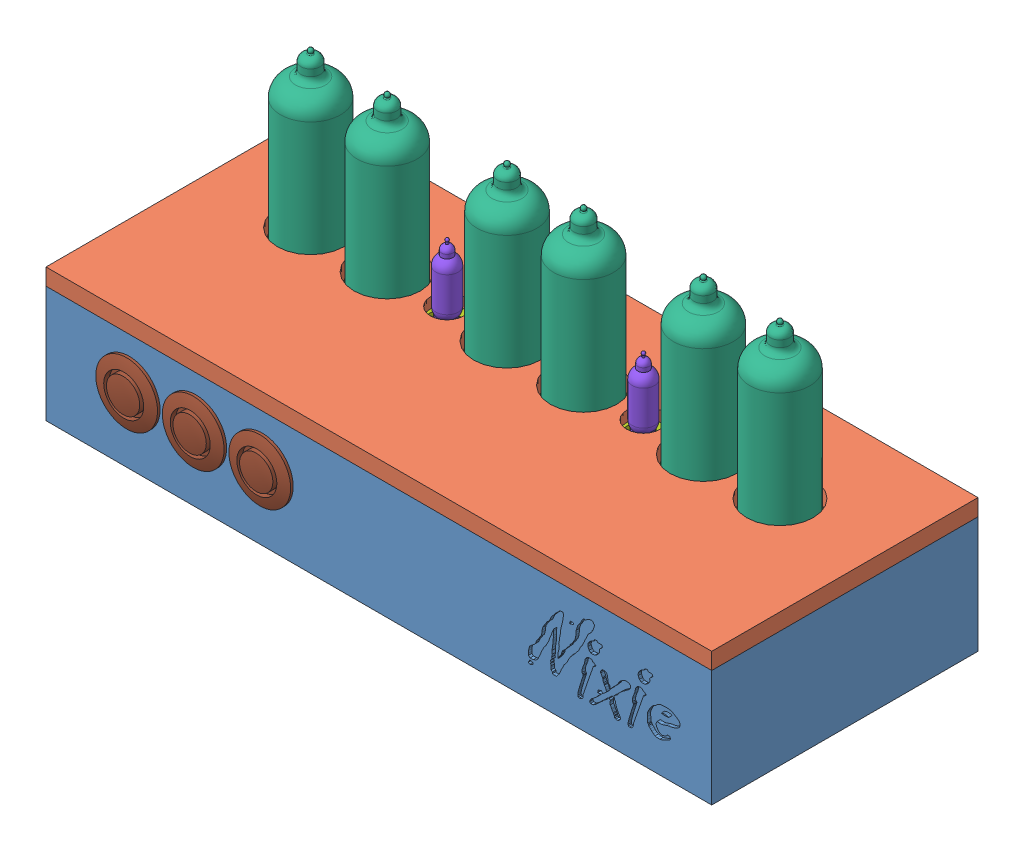
SolidWorks assembly NixieClock, configuration Predeterminado. Lengths in mm.
Overall size (200 86.82 84.28).
32 component instances, 11 part files, 89 mates.
Components (placement in the parent):
- Box-1: Box [Predeterminado] at (5.278 35 -0.0015) x (1 0 0) z (0 -1 0) size (200 80 35)
- Acrylic-1: Acrylic [Predeterminado] at (5.278 40 -0.0015) x (-1 0 0) z (0 -1 0) size (200 80 5)
- Magnet-1: Magnet [Predeterminado] at (101.528 33 36.2485) x (-0.923728 0 -0.383049) z (0 1 0) size (5 5 2)
- Magnet-2: Magnet [Predeterminado] at (101.528 33 -36.2515) x (-0.923728 0 -0.383049) z (0 1 0) size (5 5 2)
- Magnet-3: Magnet [Predeterminado] at (-90.972 33 36.2485) x (-0.923728 0 -0.383049) z (0 1 0) size (5 5 2)
- Magnet-4: Magnet [Predeterminado] at (-90.972 33 -36.2515) x (-0.923728 0 -0.383049) z (0 1 0) size (5 5 2)
- Jack5.5x2.1-1: Jack5.5x2.1 [Predeterminado] at (86.528 23.75 -42.0015) x (0 0 1) z (1 0 0) size (24.25 15.02 15.02)
- Magnet-5: Magnet [Predeterminado] at (101.528 35 36.2485) x (-0.923728 0 -0.383049) z (0 1 0) size (5 5 2)
- Magnet-6: Magnet [Predeterminado] at (101.528 35 -36.2515) x (0.923728 0 0.383049) z (0 1 0) size (5 5 2)
- Magnet-7: Magnet [Predeterminado] at (-90.972 35 36.2485) x (-0.923728 0 -0.383049) z (0 1 0) size (5 5 2)
- Magnet-9: Magnet [Predeterminado] at (-90.972 35 -36.2515) x (-0.923728 0 -0.383049) z (0 1 0) size (5 5 2)
- PCB-SPC-1: PCB-SPC [Predeterminado] at (-79.722 12.9115 19.9985) x (0.499897 0 -0.866085) z (0 1 0) size (6 5.2 16)
- PCB-SPC-2: PCB-SPC [Predeterminado] at (90.278 28.9115 -20.0015) x (1 0 0.000119) z (0 -1 0) size (6 5.2 16)
- PCB-SPC-3: PCB-SPC [Predeterminado] at (90.278 28.9115 19.9985) x (1 0 0.000119) z (0 -1 0) size (6 5.2 16)
- PCB-SPC-4: PCB-SPC [Predeterminado] at (-79.722 12.9115 -20.0015) x (1 0 -0.000119) z (0 1 0) size (6 5.2 16)
- NX-IN14-1: NX-IN14 [Predeterminado] at (75.778 60.573 -10.0016) x (1 0 0) z (0 0 1) size (18 60.3 18)
- Nixie-Board-1-1: Nixie-Board-1 [Predeterminado] at (-84.722 29.323 24.9985) x (1 0 0) z (0 1 0) size (180 50 23.76)
- NX-IN14-2: NX-IN14 [Predeterminado] at (52.778 60.573 -10.0016) x (1 0 0) z (0 0 1) size (18 60.3 18)
- NX-IN14-3: NX-IN14 [Predeterminado] at (16.778 60.573 -10.0016) x (1 0 0) z (0 0 1) size (18 60.3 18)
- NX-IN14-4: NX-IN14 [Predeterminado] at (-6.222 60.573 -10.0016) x (1 0 0) z (0 0 1) size (18 60.3 18)
- NX-IN14-5: NX-IN14 [Predeterminado] at (-42.222 60.573 -10.0016) x (1 0 0) z (0 0 1) size (18 60.3 18)
- NX-IN14-6: NX-IN14 [Predeterminado] at (-65.222 60.573 -10.0016) x (1 0 0) z (0 0 1) size (18 60.3 18)
- NX-IN3-1: NX-IN3 [Predeterminado] at (34.778 45.373 -10.0016) x (-1 0 0) z (0 0 -1) size (7 30.9 6.7)
- NX-IN3-2: NX-IN3 [Predeterminado] at (-24.222 45.373 -10.0016) x (-1 0 0) z (0 0 -1) size (7 30.9 6.7)
- Nixie-Board-2-2: Nixie-Board-2 [Predeterminado] at (-84.722 12.9115 24.9985) x (1 0 0) z (0 1 0) size (180 50 14.63)
- Leg-4: Leg [Predeterminado] at (90.278 7.5 -20.0015) x (1 0 0) z (0 1 0) size (15 25 5)
- Leg-5: Leg [Predeterminado] at (-79.722 7.5 -20.0015) x (1 0 0) z (0 1 0) size (15 25 5)
- Leg-6: Leg [Predeterminado] at (90.278 7.5 19.9985) x (1 0 0) z (0 1 0) size (15 25 5)
- Leg-7: Leg [Predeterminado] at (-79.722 7.5 19.9985) x (1 0 0) z (0 1 0) size (15 25 5)
- Button-4: Button [Predeterminado] at (-69.722 20 26.2785) x (1 0 0) z (0 -1 0) size (21.84 20.06 19.16)
- Button-5: Button [Predeterminado] at (-29.722 20 26.2785) x (1 0 0) z (0 -1 0) size (21.84 20.06 19.16)
- Button-6: Button [Predeterminado] at (-49.722 20 26.2785) x (0 1 0) z (1 0 0) size (21.84 20.06 19.16)
Mates (geometry in assembly coordinates):
- Coincidente1: coincident: plane of assembly; plane of assembly; plane of Box-1 through (5.278 33 -0.0015) normal (0 1 0); plane of Magnet-1 through (101.528 33 36.2485) normal (0 -1 0)
- Concéntrica1: concentric: circle of assembly; circle of assembly; circle of Box-1; circle of Magnet-1
- Coincidente2: coincident: plane of assembly; plane of assembly; plane of Box-1 through (5.278 33 -0.0015) normal (0 1 0); plane of Magnet-2 through (101.528 33 -36.2515) normal (0 -1 0)
- Concéntrica2: concentric: circle of assembly; circle of assembly; circle of Box-1; circle of Magnet-2
- Coincidente3: coincident: plane of assembly; plane of assembly; plane of Box-1 through (5.278 33 -0.0015) normal (0 1 0); plane of Magnet-3 through (-90.972 33 36.2485) normal (0 -1 0)
- Concéntrica3: concentric: circle of assembly; circle of assembly; circle of Box-1; circle of Magnet-3
- Coincidente4: coincident: plane of assembly; plane of assembly; plane of Box-1 through (5.278 33 -0.0015) normal (0 1 0); plane of Magnet-4 through (-90.972 33 -36.2515) normal (0 -1 0)
- Concéntrica4: concentric: circle of assembly; circle of assembly; circle of Box-1; circle of Magnet-4
- Concéntrica5: concentric: circle of assembly; circle of assembly; circle of Box-1; circle of Jack5.5x2.1-1
- Coincidente5: coincident: plane of assembly; plane of assembly; plane of Box-1 through (-94.722 0 -40.0015) normal (0 0 -1); plane of Jack5.5x2.1-1 through (80.278 17.5 -40.0015) normal (0 0 1)
- Paralelo1: parallel: plane of assembly; plane of assembly; plane of Box-1 through (5.278 7.5 -0.0015) normal (0 1 0); plane of Jack5.5x2.1-1 through (85.278 13.9 -17.7515) normal (0 -1 0)
- Coincidente17: coincident: plane of assembly; plane of assembly; plane of Acrylic-1 through (101.528 37 36.2485) normal (0 -1 0); plane of Magnet-5 through (101.528 37 36.2485) normal (0 1 0)
- Coincidente19: coincident: plane of assembly; plane of assembly; plane of Acrylic-1 through (101.528 37 36.2485) normal (0 -1 0); plane of Magnet-5 through (101.528 37 36.2485) normal (0 1 0)
- Coincidente20: coincident: circle of assembly; circle of assembly; circle of Acrylic-1; circle of Magnet-5
- Coincidente21: coincident: plane of assembly; plane of assembly; plane of Acrylic-1 through (101.528 37 -36.2515) normal (0 -1 0); plane of Magnet-6 through (101.528 37 -36.2515) normal (0 1 0)
- Concéntrica10: concentric: circle of assembly; circle of assembly; circle of Acrylic-1; circle of Magnet-6
- Coincidente24: coincident: plane of assembly; plane of assembly; plane of Acrylic-1 through (-90.972 37 36.2485) normal (0 -1 0); plane of Magnet-7 through (-90.972 37 36.2485) normal (0 1 0)
- Concéntrica11: concentric: circle of assembly; circle of assembly; circle of Acrylic-1; circle of Magnet-7
- Coincidente26: coincident: plane of assembly; plane of assembly; plane of Acrylic-1 through (-90.972 37 -36.2515) normal (0 -1 0); plane of Magnet-9 through (-90.972 37 -36.2515) normal (0 1 0)
- Concéntrica12: concentric: circle of assembly; circle of assembly; circle of Acrylic-1; circle of Magnet-9
- Coincidente28: coincident: plane of assembly; plane of assembly; plane of Acrylic-1 through (5.278 35 -0.0015) normal (0 -1 0); plane of Box-1 through (5.278 35 -0.0015) normal (0 1 0)
- Coincidente36: coincident: plane of assembly; plane of assembly; plane of Acrylic-1 through (105.278 35 39.9985) normal (1 0 0); plane of Box-1 through (105.278 0 -40.0015) normal (1 0 0)
- Concéntrica14: concentric: circle of assembly; circle of assembly; circle of NX-IN14-1; circle of Nixie-Board-1-1
- Paralelo4: parallel: line of assembly; line of assembly; line of PCB-SPC-2 through (88.778 28.9115 -22.5996) axis (1 0 0); line of Nixie-Board-1-1 through (95.278 29.323 -25.0015) axis (-1 0 0)
- Coincidente55: coincident: plane of PCB-SPC-2 through (90.278 28.9115 -20.0015) normal (0 1 0); plane of Nixie-Board-1-1 through (-84.722 28.9115 24.9985) normal (0 -1 0)
- Concéntrica27: concentric: unknown of PCB-SPC-2; unknown of Nixie-Board-1-1
- Paralelo5: parallel: line of assembly; line of assembly; line of PCB-SPC-3 through (88.778 28.9115 17.4004) axis (1 0 0); line of Nixie-Board-1-1 through (-84.722 28.9115 24.9985) axis (1 0 0)
- Coincidente58: coincident: plane of PCB-SPC-3 through (90.278 28.9115 19.9985) normal (0 1 0); plane of Nixie-Board-1-1 through (-84.722 28.9115 24.9985) normal (0 -1 0)
- Concéntrica28: concentric: unknown of PCB-SPC-3; unknown of Nixie-Board-1-1
- Paralelo6: parallel: line of assembly; line of assembly; line of PCB-SPC-4 through (-78.222 28.9115 -22.5996) axis (-1 0 0); line of Nixie-Board-1-1 through (95.278 29.323 -25.0015) axis (-1 0 0)
- Coincidente61: coincident: plane of PCB-SPC-4 through (-79.722 28.9115 -20.0015) normal (0 1 0); plane of Nixie-Board-1-1 through (-84.722 28.9115 24.9985) normal (0 -1 0)
- Concéntrica29: concentric: unknown of PCB-SPC-4; unknown of Nixie-Board-1-1
- Paralelo7: parallel: line of assembly; line of assembly; line of PCB-SPC-1 through (-78.222 28.9115 17.4004) axis (-1 0 0); line of Nixie-Board-1-1 through (-84.722 28.9115 24.9985) axis (1 0 0)
- Coincidente64: coincident: plane of PCB-SPC-1 through (-79.722 28.9115 19.9985) normal (0 1 0); plane of Nixie-Board-1-1 through (-84.722 28.9115 24.9985) normal (0 -1 0)
- Concéntrica30: concentric: unknown of PCB-SPC-1; unknown of Nixie-Board-1-1
- Paralelo8: parallel: line of assembly; line of assembly; line of Box-1 through (-94.722 35 -40.0015) axis (1 0 0); line of Nixie-Board-1-1 through (95.278 29.323 -25.0015) axis (-1 0 0)
- Paralelo9: parallel: line of Box-1 through (-94.722 0 -40.0015) axis (0 1 0); line of PCB-SPC-4 through (-81.222 28.9115 -22.5996) axis (0 -1 0)
- Coincidente72: coincident: plane of PCB-SPC-2 through (90.278 12.9115 -20.0015) normal (0 -1 0); plane of Nixie-Board-2-2 through (-84.722 12.9115 24.9985) normal (0 1 0)
- Paralelo11: parallel: line of Nixie-Board-2-2 through (-84.722 12.5 -25.0015) axis (0 0 1); line of Nixie-Board-1-1 through (-84.722 29.323 -25.0015) axis (0 0 1)
- Concéntrica32: concentric: unknown of Nixie-Board-1-1; unknown of Nixie-Board-2-2
- Coincidente78: coincident: plane of Nixie-Board-2-2 through (-84.722 12.5 24.9985) normal (0 -1 0); plane of Leg-4 through (90.278 12.5 -20.0015) normal (0 1 0)
- Paralelo12: parallel: line of Nixie-Board-2-2 through (-84.722 12.5 -25.0015) axis (0 0 1); line of Leg-7 through (-87.222 7.5 7.4985) axis (0 0 1)
- Paralelo13: parallel: line of Nixie-Board-2-2 through (-84.722 12.5 -25.0015) axis (0 0 1); line of Leg-5 through (-87.222 7.5 -32.5015) axis (0 0 1)
- Paralelo14: parallel: line of Nixie-Board-2-2 through (95.278 12.9115 24.9985) axis (0 0 -1); line of Leg-6 through (82.778 7.5 7.4985) axis (0 0 1)
- Paralelo15: parallel: line of Nixie-Board-2-2 through (-84.722 12.5 -25.0015) axis (0 0 1); line of Leg-4 through (82.778 7.5 -32.5015) axis (0 0 1)
- Concéntrica33: concentric: unknown of Nixie-Board-2-2; circle of Leg-5
- Concéntrica34: concentric: unknown of Nixie-Board-2-2; unknown of Leg-7
- Concéntrica35: concentric: unknown of Nixie-Board-2-2; unknown of Leg-6
- Concéntrica36: concentric: unknown of Nixie-Board-2-2; unknown of Leg-4
- Coincidente81: coincident: plane of Box-1 through (5.278 7.5 -0.0015) normal (0 1 0); plane of Leg-7 through (-79.722 7.5 19.9985) normal (0 -1 0)
- Concéntrica37: concentric: circle of assembly; circle of assembly; circle of Magnet-2; circle of Magnet-6
- Coincidente87: coincident: line of Box-1 through (97.778 7.5 -32.5015) axis (-1 0 0); line of Leg-5 through (-72.222 7.5 -32.5015) axis (-1 0 0)
- Coincidente89: coincident: line of Box-1 through (-87.222 7.5 -32.5015) axis (0 0 1); line of Leg-5 through (-87.222 7.5 -32.5015) axis (0 0 1)
- Coincidente92: coincident: plane of assembly; plane of Box-1 through (5.278 0 -0.0015) normal (0 -1 0); point of assembly
- Concéntrica38: concentric: circle of assembly; circle of assembly; circle of NX-IN14-1; circle of Nixie-Board-1-1
- Coincidente93: coincident: plane of assembly; plane of assembly; plane of NX-IN14-1 through (75.778 34.323 -10.0016) normal (0 -1 0); plane of Nixie-Board-1-1 through (75.778 34.323 -10.0016) normal (0 1 0)
- Concéntrica41: concentric: circle of assembly; circle of assembly; circle of Nixie-Board-1-1; circle of NX-IN14-2
- Concéntrica42: concentric: circle of Nixie-Board-1-1; circle of NX-IN14-2
- Coincidente95: coincident: plane of Nixie-Board-1-1 through (52.778 34.323 -10.0016) normal (0 1 0); plane of NX-IN14-2 through (52.778 34.323 -10.0016) normal (0 -1 0)
- Concéntrica43: concentric: circle of assembly; circle of assembly; circle of Nixie-Board-1-1; circle of NX-IN14-3
- Concéntrica44: concentric: circle of Nixie-Board-1-1; circle of NX-IN14-3
- Coincidente96: coincident: plane of Nixie-Board-1-1 through (16.778 34.323 -10.0016) normal (0 1 0); plane of NX-IN14-3 through (16.778 34.323 -10.0016) normal (0 -1 0)
- Concéntrica45: concentric: circle of assembly; circle of assembly; circle of Nixie-Board-1-1; circle of NX-IN3-1
- Paralelo16: parallel: line of Nixie-Board-1-1 through (32.778 36.823 -12.5016) axis (1 0 0); line of NX-IN3-1 through (31.778 34.8354 -9.1516) axis (1 0 0)
- Coincidente98: coincident: plane of Nixie-Board-1-1 through (34.778 33.323 -10.0016) normal (0 1 0); plane of NX-IN3-1 through (33.528 33.323 -8.6006) normal (0 -1 0)
- Concéntrica47: concentric: circle of assembly; circle of assembly; circle of Nixie-Board-1-1; circle of NX-IN14-4
- Concéntrica48: concentric: circle of Nixie-Board-1-1; circle of NX-IN14-4
- Coincidente99: coincident: plane of Nixie-Board-1-1 through (-6.222 34.323 -10.0016) normal (0 1 0); plane of NX-IN14-4 through (-6.222 34.323 -10.0016) normal (0 -1 0)
- Concéntrica49: concentric: circle of assembly; circle of assembly; circle of Nixie-Board-1-1; circle of NX-IN3-2
- Paralelo17: parallel: line of Nixie-Board-1-1 through (-26.222 36.823 -12.5016) axis (1 0 0); line of NX-IN3-2 through (-27.222 34.8354 -9.1516) axis (1 0 0)
- Coincidente104: coincident: plane of Nixie-Board-1-1 through (-24.222 33.323 -10.0016) normal (0 1 0); plane of NX-IN3-2 through (-22.972 33.323 -8.6006) normal (0 -1 0)
- Concéntrica50: concentric: circle of assembly; circle of assembly; circle of Nixie-Board-1-1; circle of NX-IN14-5
- Concéntrica51: concentric: circle of Nixie-Board-1-1; circle of NX-IN14-5
- Coincidente105: coincident: plane of Nixie-Board-1-1 through (-42.222 34.323 -10.0016) normal (0 1 0); plane of NX-IN14-5 through (-42.222 34.323 -10.0016) normal (0 -1 0)
- Concéntrica52: concentric: circle of assembly; circle of assembly; circle of Nixie-Board-1-1; circle of NX-IN14-6
- Concéntrica53: concentric: circle of Nixie-Board-1-1; circle of NX-IN14-6
- Coincidente106: coincident: plane of Nixie-Board-1-1 through (-65.222 34.323 -10.0016) normal (0 1 0); plane of NX-IN14-6 through (-65.222 34.323 -10.0016) normal (0 -1 0)
- Coincidente107: coincident: plane of Nixie-Board-2-2 through (-84.722 12.5 24.9985) normal (0 -1 0); plane of Leg-6 through (90.278 12.5 19.9985) normal (0 1 0)
- Coincidente108: coincident: plane of Nixie-Board-2-2 through (-84.722 12.5 24.9985) normal (0 -1 0); plane of Leg-7 through (-79.722 12.5 19.9985) normal (0 1 0)
- Coincidente109: coincident: plane of Nixie-Board-2-2 through (-84.722 12.5 24.9985) normal (0 -1 0); plane of Leg-5 through (-79.722 12.5 -20.0015) normal (0 1 0)
- Concéntrica54: concentric: circle of assembly; circle of assembly; circle of Box-1; circle of Button-4
- Coincidente110: coincident: plane of Box-1 through (-94.722 0 39.9985) normal (0 0 1); plane of Button-4 through (-60.0812 10.3592 39.9985) normal (0 0 -1)
- Concéntrica55: concentric: circle of assembly; circle of assembly; circle of Box-1; circle of Button-6
- Coincidente111: coincident: plane of assembly; plane of assembly; plane of Box-1 through (-94.722 0 39.9985) normal (0 0 1); plane of Button-6 through (-40.0812 29.6408 39.9985) normal (0 0 -1)
- Concéntrica56: concentric: circle of assembly; circle of assembly; circle of Box-1; circle of Button-5
- Coincidente112: coincident: plane of Box-1 through (-94.722 0 39.9985) normal (0 0 1); plane of ? through (-16.123 19.022 39.9985) normal (0 0 -1)
- Paralelo18: parallel: line of Nixie-Board-1-1 through (-84.722 29.323 24.9985) axis (1 0 0); line of Button-4 through (-70.917 24.95 22.5185) axis (1 0 0)
- Paralelo19: parallel: line of assembly; line of assembly; line of Nixie-Board-1-1 through (-84.722 29.323 24.9985) axis (1 0 0); line of Button-6 through (-48.527 24.95 22.5185) axis (-1 0 0)
- Paralelo20: parallel: line of assembly; line of assembly; line of Nixie-Board-1-1 through (-84.722 29.323 24.9985) axis (1 0 0); line of Button-5 through (-30.917 24.95 22.5185) axis (1 0 0)
